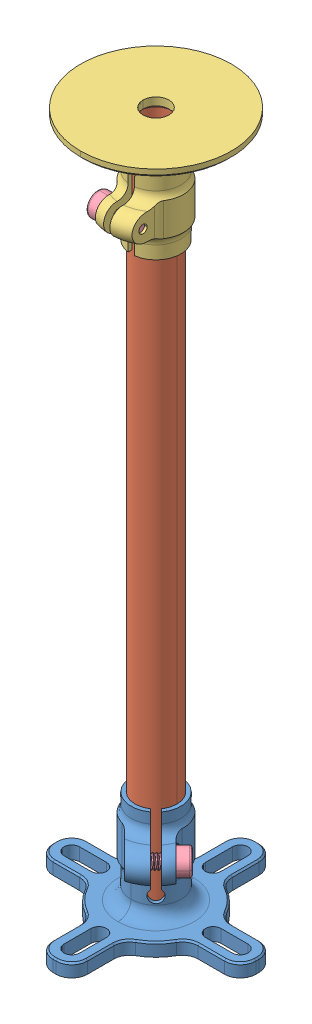
SolidWorks assembly GPS-M8N-M9N-Mount.stp, configuration Default. Lengths in mm.
Overall size (39 134.5 39).
5 component instances, 4 part files, 0 mates.
Components (placement in the parent):
- RTK-ZHIJIA-ZUO-8-C1.stp-1: RTK-ZHIJIA-ZUO-8-C1.stp [Default] x (1 0 0) z (0 1 0) size (39 39 20.5)
- GUAN-RTK-JIA-8.stp-1: GUAN-RTK-JIA-8.stp [Default] at (0 67.5 0) x (1 0 0) z (0 -1 0) size (8 8 130)
- M8P-ZHIJIA-TUOPAN-C1.stp-1: M8P-ZHIJIA-TUOPAN-C1.stp [Default] at (0 133 0) x (1 0 0) z (0 -1 0) size (29 29 22)
- GB70-M25-6.stp-1: GB70-M25-6.stp [Default] at (-2.5 119.5 6.5) x (0 -1 0) z (-1 0 0) size (4.48 4.48 8.24)
- GB70-M25-6.stp-2: GB70-M25-6.stp [Default] at (6.5054 13.5 2.687) x (-0.707107 0 -0.707107) z (0.707107 0 -0.707107) size (4.48 4.48 8.24)
